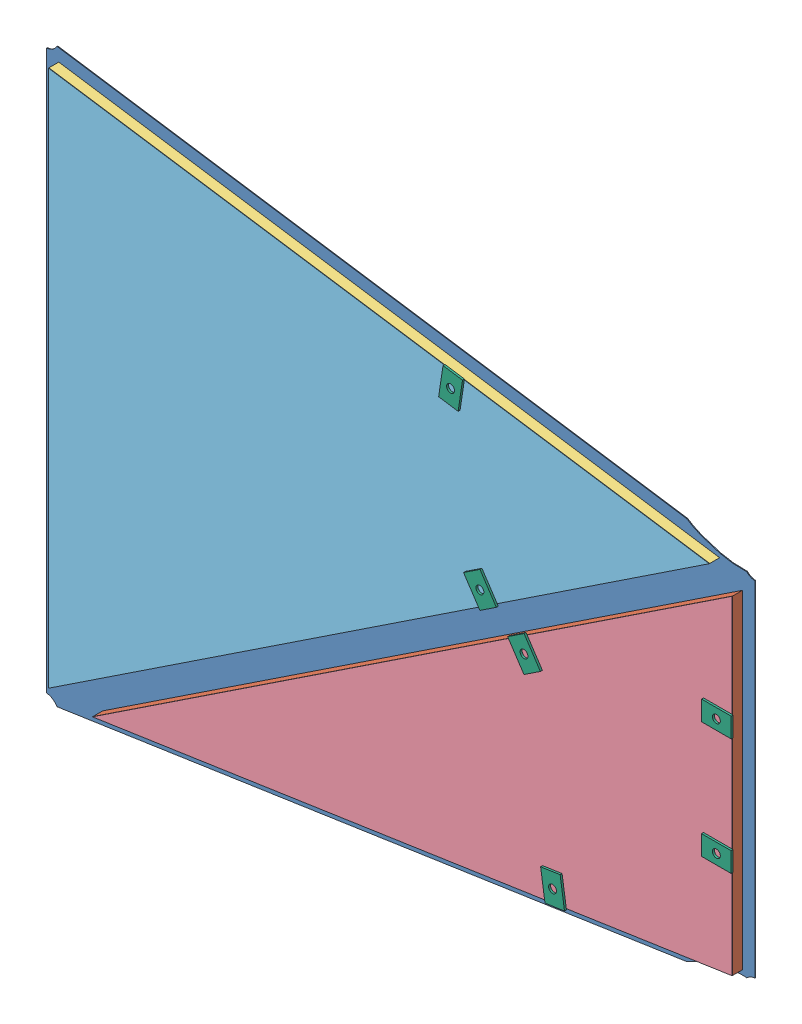
SolidWorks assembly PUTM-F-MS-CO-Floor, configuration Default. Lengths in mm.
Overall size (718.24 579.81 13.25).
11 component instances, 6 part files, 39 mates.
Components (placement in the parent):
- PUTM-F-MS-CO-Highercarbon-1: PUTM-F-MS-CO-Highercarbon [Default] at origin size (718.24 579.81 0.75)
- PUTM-F-MS-CO-Lefr_Honeycomb-1: PUTM-F-MS-CO-Lefr_Honeycomb [Default] at (0 0 10.75) x (1 0 0) z (0 0 -1) size (648.64 430.17 10)
- PUTM-F-MS-CO-Right_Honeycomb-1: PUTM-F-MS-CO-Right_Honeycomb [Default] at (0 0 10.75) x (1 0 0) z (0 0 -1) size (670.05 544.53 10)
- PUTM-F-MS-CO-Left_Carbon-1: PUTM-F-MS-CO-Left_Carbon [Default] at (0 0 11.25) x (1 0 0) z (0 0 -1) size (648.64 430.17 0.5)
- PUTM-F-MS-CO-Right_Carbon-1: PUTM-F-MS-CO-Right_Carbon [Default] at (0 0 11.25) x (1 0 0) z (0 0 -1) size (670.05 544.53 0.5)
- PUTM-F-MS-CO-Flat_bar-1: PUTM-F-MS-CO-Flat_bar [Default] at (-209.6801 36.1075 11.25) x (0 1 0) z (0 0 1) size (20 30 2)
- PUTM-F-MS-CO-Flat_bar-2: PUTM-F-MS-CO-Flat_bar [Default] at (-209.6801 -82.0764 11.25) x (0 1 0) z (0 0 1) size (20 30 2)
- PUTM-F-MS-CO-Flat_bar-3: PUTM-F-MS-CO-Flat_bar [Default] at (-398.4366 -202.4528 11.25) x (0.98901 0.147851 0) z (0 0 1) size (20 30 2)
- PUTM-F-MS-CO-Flat_bar-8: PUTM-F-MS-CO-Flat_bar [Default] at (-482.0635 214.9546 11.25) x (-0.98901 0.147851 0) z (0 0 1) size (20 30 2)
- PUTM-F-MS-CO-Flat_bar-13: PUTM-F-MS-CO-Flat_bar [Default] at (-419.6588 23.6339 11.25) x (-0.833387 -0.55269 0) z (0 0 1) size (20 30 2)
- PUTM-F-MS-CO-Flat_bar-14: PUTM-F-MS-CO-Flat_bar [Default] at (-464.4451 21.5305 11.25) x (0.833387 0.55269 0) z (0 0 1) size (20 30 2)
Mates (geometry in assembly coordinates):
- Wspólnie1: coincident anti-aligned: plane of PUTM-F-MS-CO-Highercarbon-1 through (-235.1084 181.3069 0.75) normal (0 0 1); plane of PUTM-F-MS-CO-Lefr_Honeycomb-1 through (0 0 0.75) normal (0 0 -1)
- Odległość1: distance = 12.5 mm: line of PUTM-F-MS-CO-Lefr_Honeycomb-1 through (-210.6801 -173.3732 0.75) axis (-0.98901 -0.147851 0); line of PUTM-F-MS-CO-Highercarbon-1 through (-905.6574 -289.9071 0.75) axis (0.98901 0.147851 0)
- Odległość2: distance = 12.5 mm: line of PUTM-F-MS-CO-Lefr_Honeycomb-1 through (-210.6801 159.8256 0.75) axis (0 -1 0); line of PUTM-F-MS-CO-Highercarbon-1 through (-198.1801 -174.3434 0.75) axis (0 1 0)
- Wspólnie4: coincident anti-aligned: plane of PUTM-F-MS-CO-Highercarbon-1 through (-235.1084 181.3069 0.75) normal (0 0 1); plane of PUTM-F-MS-CO-Right_Honeycomb-1 through (0 0 0.75) normal (0 0 -1)
- Odległość4: distance = 12.5 mm: line of PUTM-F-MS-CO-Right_Honeycomb-1 through (-233.8753 176.8408 0.75) axis (-0.98901 0.147851 0); line of PUTM-F-MS-CO-Highercarbon-1 through (-267.1164 194.449 0.75) axis (-0.98901 0.147851 0)
- Wspólnie7: coincident anti-aligned: plane of PUTM-F-MS-CO-Lefr_Honeycomb-1 through (0 0 10.75) normal (0 0 1); plane of PUTM-F-MS-CO-Left_Carbon-1 through (0 0 10.75) normal (0 0 -1)
- Wspólnie8: coincident aligned: line of PUTM-F-MS-CO-Lefr_Honeycomb-1 through (-210.6801 -173.3732 10.75) axis (-0.98901 -0.147851 0); line of PUTM-F-MS-CO-Left_Carbon-1 through (-210.6801 -173.3732 10.75) axis (-0.98901 -0.147851 0)
- Wspólnie9: coincident aligned: line of PUTM-F-MS-CO-Lefr_Honeycomb-1 through (-210.6801 159.8256 10.75) axis (0 -1 0); line of PUTM-F-MS-CO-Left_Carbon-1 through (-210.6801 159.8256 10.75) axis (0 -1 0)
- Wspólnie10: coincident anti-aligned: plane of PUTM-F-MS-CO-Right_Honeycomb-1 through (0 0 10.75) normal (0 0 1); plane of PUTM-F-MS-CO-Right_Carbon-1 through (0 0 10.75) normal (0 0 -1)
- Wspólnie11: coincident aligned: line of PUTM-F-MS-CO-Right_Honeycomb-1 through (-233.8753 176.8408 10.75) axis (-0.98901 0.147851 0); line of PUTM-F-MS-CO-Right_Carbon-1 through (-233.8753 176.8408 10.75) axis (-0.98901 0.147851 0)
- Wspólnie13: coincident anti-aligned: plane of PUTM-F-MS-CO-Left_Carbon-1 through (0 0 11.25) normal (0 0 1); plane of PUTM-F-MS-CO-Flat_bar-1 through (-209.6801 36.1075 11.25) normal (0 0 -1)
- Odległość5: distance = 1 mm: line of PUTM-F-MS-CO-Flat_bar-1 through (-209.6801 36.1075 11.25) axis (0 1 0); line of PUTM-F-MS-CO-Left_Carbon-1 through (-210.6801 159.8256 11.25) axis (0 -1 0)
- Wspólnie15: coincident anti-aligned: plane of PUTM-F-MS-CO-Left_Carbon-1 through (0 0 11.25) normal (0 0 1); plane of PUTM-F-MS-CO-Flat_bar-2 through (-209.6801 -82.0764 11.25) normal (0 0 -1)
- Odległość6: distance = 1 mm: line of PUTM-F-MS-CO-Flat_bar-2 through (-209.6801 -82.0764 11.25) axis (0 1 0); line of PUTM-F-MS-CO-Left_Carbon-1 through (-210.6801 159.8256 11.25) axis (0 -1 0)
- Wspólnie17: coincident anti-aligned: plane of PUTM-F-MS-CO-Left_Carbon-1 through (0 0 11.25) normal (0 0 1); plane of PUTM-F-MS-CO-Flat_bar-3 through (-398.4366 -202.4528 11.25) normal (0 0 -1)
- Odległość7: distance = 1 mm: line of PUTM-F-MS-CO-Flat_bar-3 through (-398.4366 -202.4528 11.25) axis (0.98901 0.147851 0); line of PUTM-F-MS-CO-Left_Carbon-1 through (-210.6801 -173.3732 11.25) axis (-0.98901 -0.147851 0)
- Wspólnie19: coincident anti-aligned: plane of PUTM-F-MS-CO-Left_Carbon-1 through (0 0 11.25) normal (0 0 1); plane of PUTM-F-MS-CO-Flat_bar-4 through (-594.3227 -216.57 11.25) normal (0 0 -1)
- Odległość8: distance = 1 mm: line of PUTM-F-MS-CO-Flat_bar-4 through (-598.1801 -232.3133 11.25) axis (0.98901 0.147851 0); line of PUTM-F-MS-CO-Left_Carbon-1 through (-210.6801 -173.3732 11.25) axis (-0.98901 -0.147851 0)
- Wspólnie21: coincident anti-aligned: plane of PUTM-F-MS-CO-Right_Carbon-1 through (0 0 11.25) normal (0 0 1); plane of PUTM-F-MS-CO-Flat_bar-5 through (-889.9239 -146.2568 11.25) normal (0 0 -1)
- Wspólnie23: coincident anti-aligned: plane of PUTM-F-MS-CO-Right_Carbon-1 through (0 0 11.25) normal (0 0 1); plane of PUTM-F-MS-CO-Flat_bar-6 through (-889.9239 124.2609 11.25) normal (0 0 -1)
- Wspólnie25: coincident anti-aligned: plane of PUTM-F-MS-CO-Right_Carbon-1 through (0 0 11.25) normal (0 0 1); plane of PUTM-F-MS-CO-Flat_bar-7 through (-747.4762 239.4655 11.25) normal (0 0 -1)
- Odległość11: distance = 1 mm: line of PUTM-F-MS-CO-Flat_bar-7 through (-735.3684 252.8221 11.25) axis (-0.98901 0.147851 0); line of PUTM-F-MS-CO-Right_Carbon-1 through (-233.8753 176.8408 11.25) axis (-0.98901 0.147851 0)
- Wspólnie27: coincident anti-aligned: plane of PUTM-F-MS-CO-Right_Carbon-1 through (0 0 11.25) normal (0 0 1); plane of PUTM-F-MS-CO-Flat_bar-8 through (-482.0635 214.9546 11.25) normal (0 0 -1)
- Odległość12: distance = 1 mm: line of PUTM-F-MS-CO-Flat_bar-8 through (-482.0635 214.9546 11.25) axis (-0.98901 0.147851 0); line of PUTM-F-MS-CO-Right_Carbon-1 through (-233.8753 176.8408 11.25) axis (-0.98901 0.147851 0)
- Wspólnie40: coincident aligned: line of PUTM-F-MS-CO-Left_Carbon-1 through (-859.317 -270.3406 11.25) axis (0.833387 0.55269 0); line of PUTM-F-MS-CO-Medium_Flat_bar-3 through (-463.6532 -7.9424 11.25) axis (0.833387 0.55269 0)
- Równolegle10: parallel anti-aligned: plane of PUTM-F-MS-CO-Left_Carbon-1 through (0 0 11.25) normal (0 0 1); plane of PUTM-F-MS-CO-Medium_Flat_bar-3 through (-489.899 31.6331 11.4241) normal (0 0 -1)
- Wspólnie45: coincident anti-aligned: line of PUTM-F-MS-CO-Right_Carbon-1 through (-233.8753 176.8408 11.25) axis (-0.833387 -0.55269 0); line of PUTM-F-MS-CO-Medium_Flat_bar-4 through (-676.2339 -116.5248 11.25) axis (0.833387 0.55269 0)
- Równolegle11: parallel anti-aligned: plane of PUTM-F-MS-CO-Left_Carbon-1 through (0 0 11.25) normal (0 0 1); plane of PUTM-F-MS-CO-Medium_Flat_bar-4 through (-649.9883 -156.0998 10.947) normal (0 0 -1)
- Wspólnie46: coincident anti-aligned: plane of PUTM-F-MS-CO-Left_Carbon-1 through (0 0 11.25) normal (0 0 1); plane of PUTM-F-MS-CO-Flat_bar-9 through (-635.9248 -137.7893 11.25) normal (0 0 -1)
- Odległość13: distance = 2 mm: line of PUTM-F-MS-CO-Flat_bar-9 through (-652.549 -130.8154 11.25) axis (0.833387 0.55269 0); line of PUTM-F-MS-CO-Left_Carbon-1 through (-859.317 -270.3406 11.25) axis (0.833387 0.55269 0)
- Wspólnie51: coincident anti-aligned: plane of PUTM-F-MS-CO-Right_Carbon-1 through (0 0 11.25) normal (0 0 1); plane of PUTM-F-MS-CO-Flat_bar-12 through (-687.7676 -108.5747 11.25) normal (0 0 -1)
- Odległość15: distance = 2 mm: line of PUTM-F-MS-CO-Flat_bar-12 through (-687.8111 -126.6024 11.25) axis (0.833387 0.55269 0); line of PUTM-F-MS-CO-Right_Carbon-1 through (-233.8753 176.8408 11.25) axis (-0.833387 -0.55269 0)
- Wspólnie53: coincident anti-aligned: plane of PUTM-F-MS-CO-Left_Carbon-1 through (0 0 11.25) normal (0 0 1); plane of PUTM-F-MS-CO-Flat_bar-13 through (-419.6588 23.6339 11.25) normal (0 0 -1)
- Odległość16: distance = 2 mm: line of PUTM-F-MS-CO-Flat_bar-13 through (-419.6588 23.6339 11.25) axis (-0.833387 -0.55269 0); line of PUTM-F-MS-CO-Left_Carbon-1 through (-859.317 -270.3406 11.25) axis (0.833387 0.55269 0)
- Wspólnie55: coincident anti-aligned: plane of PUTM-F-MS-CO-Right_Carbon-1 through (0 0 11.25) normal (0 0 1); plane of PUTM-F-MS-CO-Flat_bar-14 through (-464.4451 21.5305 11.25) normal (0 0 -1)
- Odległość17: distance = 2 mm: line of PUTM-F-MS-CO-Flat_bar-14 through (-464.4451 21.5305 11.25) axis (0.833387 0.55269 0); line of PUTM-F-MS-CO-Right_Carbon-1 through (-233.8753 176.8408 11.25) axis (-0.833387 -0.55269 0)
- Odległość18: distance = 249.44 mm: point of PUTM-F-MS-CO-Flat_bar-13; point of PUTM-F-MS-CO-Left_Carbon-1
- Odległość19: distance = 249.44 mm: point of PUTM-F-MS-CO-Flat_bar-9; point of PUTM-F-MS-CO-Left_Carbon-1
- Odległość20: distance = 258 mm: point of PUTM-F-MS-CO-Flat_bar-14; point of PUTM-F-MS-CO-Right_Carbon-1
